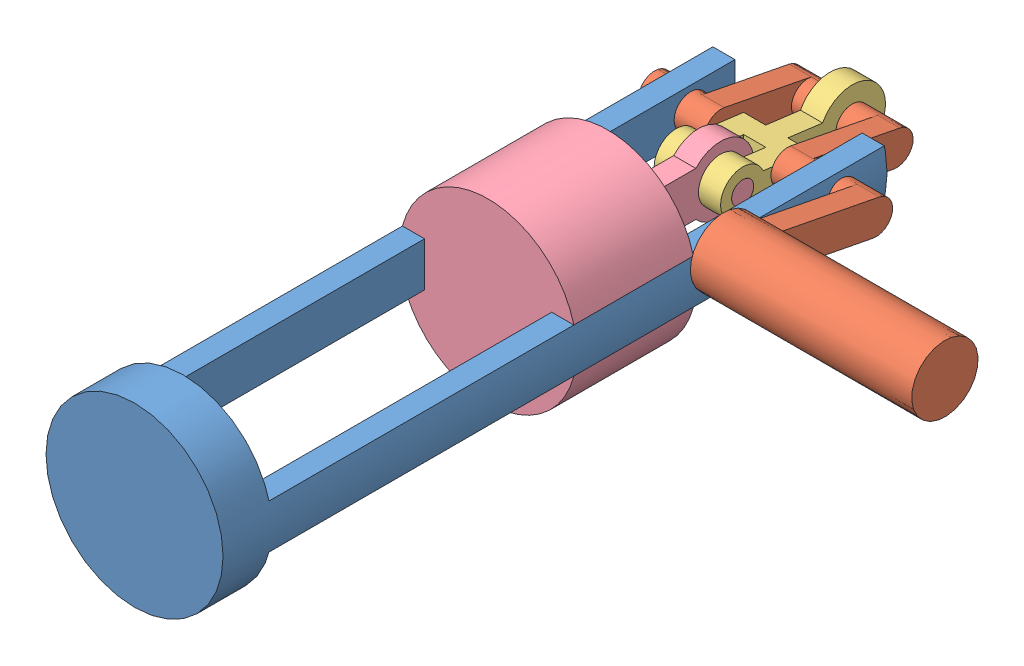
SolidWorks assembly hw07, configuration Default. Lengths in mm.
Overall size (241.3 101.6 426.79).
4 component instances, 4 part files, 7 mates.
Components (placement in the parent):
- hw07.1.base-1: hw07.1.base [Default] at (113.9217 216.2298 458.1177) size (101.6 101.6 381)
- hw07.1.crank-1: hw07.1.crank [Default] at (171.0717 230.7694 205.2577) x (1 0 0) z (0 0.190809 0.981627) size (241.3 38.1 155.58)
- hw07.1.lever-1: hw07.1.lever [Default] at (113.9217 216.2298 156.1721) x (1 0 0) z (0 0.127206 0.991876) size (38.1 38.1 107.95)
- hw07.1.piston-1: hw07.1.piston [Default] at (113.9217 216.2298 214.5921) size (98.37 101.6 146.05)
Mates (geometry in assembly coordinates):
- Coincident1: coincident anti-aligned: plane of hw07.1.base-1 through (150.4086 203.5298 105.0577) normal (0 -1 0); plane of hw07.1.piston-1 through (150.4086 203.5298 283.1721) normal (0 1 0)
- Coincident2: coincident anti-aligned: plane of hw07.1.base-1 through (150.4086 228.9298 105.0577) normal (-1 0 0); plane of hw07.1.piston-1 through (150.4086 228.9298 283.1721) normal (1 0 0)
- Coincident3: coincident aligned: circle of hw07.1.lever-1; circle of hw07.1.piston-1
- Concentric1: concentric anti-aligned: cylinder of hw07.1.crank-1 through (82.1717 206.5367 80.5911) axis (1 0 0) radius 9.525; cylinder of hw07.1.lever-1 through (120.2717 206.5367 80.5911) axis (-1 0 0) radius 9.525
- Concentric2: concentric aligned: cylinder of hw07.1.base-1 through (63.1217 216.2298 130.4577) axis (1 0 0) radius 9.525; cylinder of hw07.1.crank-1 through (132.9717 216.2298 130.4577) axis (1 0 0) radius 9.525
- Width1: width aligned: plane of hw07.1.base-1 through (77.4348 228.9298 105.0577) normal (1 0 0); plane of hw07.1.base-1 through (150.4086 228.9298 105.0577) normal (-1 0 0); plane of hw07.1.crank-1 through (94.8717 230.7694 205.2577) normal (1 0 0); plane of hw07.1.crank-1 through (132.9717 230.7694 205.2577) normal (-1 0 0)
- Angle3: planar angle = 2.949606 rad anti-aligned: line of hw07.1.base-1 through (163.1086 228.9298 105.0577) axis (0 0 1); line of hw07.1.crank-1 through (183.7717 225.5798 128.6403) axis (0 0.190809 0.981627)
